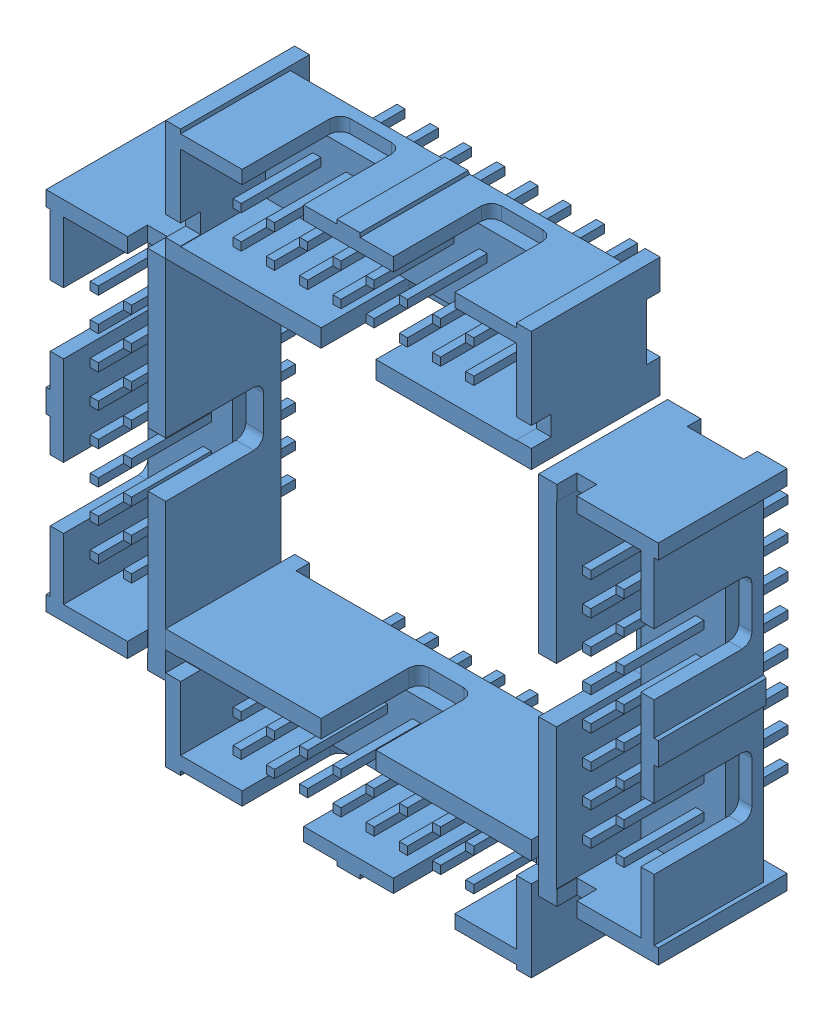
SolidWorks assembly Pic32Board-Support, configuration Défaut. Lengths in mm.
Overall size (46.79 42.79 12.9).
4 component instances, 1 part files, 9 mates.
Components (placement in the parent):
- HE10-16Way-1: HE10-16Way [Default] at (-6.8205 -0.3878 34.3917) size (27.94 9.14 12.9)
- HE10-16Way-3: HE10-16Way [Default] at (-6.8205 33.2562 34.3917) x (-1 0 0) z (0 0 1) size (27.94 9.14 12.9)
- HE10-16Way-4: HE10-16Way [Default] at (12.2815 14.7142 34.3917) x (0 1 0) z (0 0 1) size (27.94 9.14 12.9)
- HE10-16Way-5: HE10-16Way [Default] at (-25.3625 14.7142 34.3917) x (0 -1 0) z (0 0 1) size (27.94 9.14 12.9)
Mates (geometry in assembly coordinates):
- Coïncidente1: coincident aligned: plane of HE10-16Way-3 through (-21.6686 33.2562 34.3917) normal (0 0 1); plane of HE10-16Way-4 through (-2.5666 14.7142 34.3917) normal (0 0 1)
- Perpendiculaire1: perpendicular: plane of HE10-16Way-3 through (-35.6386 28.6842 34.3917) normal (0 -1 0); plane of HE10-16Way-4 through (-7.1386 28.6842 34.3917) normal (-1 0 0)
- Coïncidente4: coincident aligned: plane of HE10-16Way-4 through (-2.5666 14.7142 34.3917) normal (0 0 1); plane of HE10-16Way-5 through (-40.2106 14.7142 34.3917) normal (0 0 1)
- Coïncidente5: coincident aligned: plane of HE10-16Way-4 through (-7.1386 0.7442 34.3917) normal (0 -1 0); plane of HE10-16Way-5 through (-44.7826 0.7442 34.3917) normal (0 -1 0)
- Distance1: distance = 28.5 mm anti-aligned: plane of HE10-16Way-4 through (7.7095 28.6842 34.3917) normal (-1 0 0); plane of HE10-16Way-5 through (-20.7905 0.7442 34.3917) normal (1 0 0)
- Coïncidente8: coincident anti-aligned: line of HE10-16Way-3 through (-35.6386 28.6842 34.3917) axis (0 0 -1); line of HE10-16Way-5 through (-35.6386 28.6842 24.5365) axis (0 0 1)
- Coïncidente11: coincident aligned: plane of HE10-16Way-1 through (-6.8205 -0.3878 34.3917) normal (0 0 1); plane of HE10-16Way-5 through (-40.2106 14.7142 34.3917) normal (0 0 1)
- Distance2: distance = 24.5 mm anti-aligned: plane of HE10-16Way-3 through (-20.7905 28.6842 34.3917) normal (0 -1 0); plane of HE10-16Way-1 through (7.1495 4.1842 34.3917) normal (0 1 0)
- Coïncidente14: coincident aligned: plane of HE10-16Way-1 through (-20.7905 4.1842 34.3917) normal (-1 0 0); plane of HE10-16Way-3 through (-20.7905 37.8282 34.3917) normal (-1 0 0)
